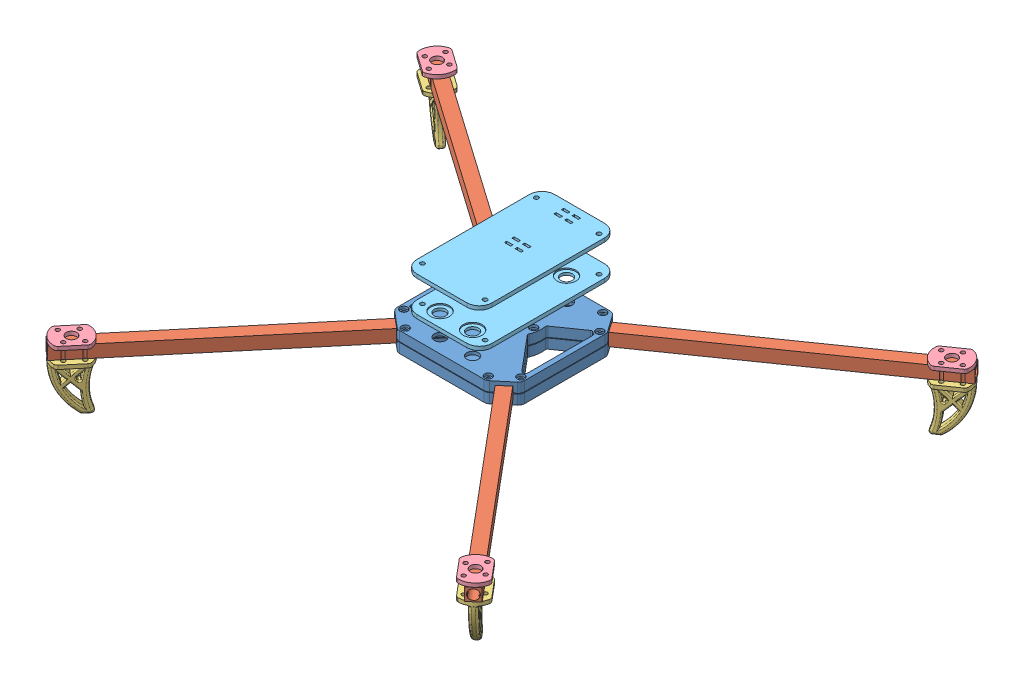
SolidWorks assembly Carbon Arm Quad, configuration Default. Lengths in mm.
Overall size (449.5 99 372.79).
16 component instances, 5 part files, 45 mates.
Components (placement in the parent):
- Center Section-1: Center Section [Bottom] at origin size (101.58 8.23 97.56)
- Center Section-2: Center Section [Top] x (-1 0 0) z (0 0 1) size (101.58 8.23 97.56)
- Carbon Arm-1: Carbon Arm [Default] at (-9.6418 0 11.4907) x (0.766044 0 0.642788) z (-0.642788 0 0.766044) size (10 10 250)
- Carbon Arm-2: Carbon Arm [Default] at (-12.2873 0 -8.6036) x (-0.573576 0 0.819152) z (-0.819152 0 -0.573576) size (10 10 250)
- Carbon Arm-5: Carbon Arm [Default] at (12.2873 0 -8.6036) x (-0.573576 0 -0.819152) z (0.819152 0 -0.573576) size (10 10 250)
- Carbon Arm-6: Carbon Arm [Default] at (9.6418 0 11.4907) x (0.766044 0 -0.642788) z (0.642788 0 0.766044) size (10 10 250)
- Bottom Motor Mount-1: Bottom Motor Mount [Default] at (-205.6072 5 -143.9677) x (-0.573576 0 0.819152) z (-0.819152 0 -0.573576) size (20 40 32.07)
- Top Motor Mount-1: Top Motor Mount [Default] at (-205.6072 5 -143.9677) x (-0.573576 0 0.819152) z (-0.819152 0 -0.573576) size (20 3 28)
- Bottom Motor Mount-3: Bottom Motor Mount [Default] at (-161.3397 5 192.2772) x (0.766044 0 0.642788) z (-0.642788 0 0.766044) size (20 40 32.07)
- Top Motor Mount-2: Top Motor Mount [Default] at (-161.3397 5 192.2772) x (0.766044 0 0.642788) z (-0.642788 0 0.766044) size (20 3 28)
- Bottom Motor Mount-5: Bottom Motor Mount [Default] at (161.3397 5 192.2772) x (0.766044 0 -0.642788) z (0.642788 0 0.766044) size (20 40 32.07)
- Top Motor Mount-4: Top Motor Mount [Default] at (161.3397 5 192.2772) x (0.766044 0 -0.642788) z (0.642788 0 0.766044) size (20 3 28)
- Bottom Motor Mount-6: Bottom Motor Mount [Default] at (205.6072 5 -143.9677) x (-0.573576 0 -0.819152) z (0.819152 0 -0.573576) size (20 40 32.07)
- Top Motor Mount-5: Top Motor Mount [Default] at (205.6072 5 -143.9677) x (-0.573576 0 -0.819152) z (0.819152 0 -0.573576) size (20 3 28)
- Clean Plate-1: Clean Plate [Bottom] at (0 23 2.8266) size (60 3 110)
- Clean Plate-2: Clean Plate [Top] at (0 51 2.8266) size (60 3 110)
Mates (geometry in assembly coordinates):
- Distance1: distance = 0.5 mm anti-aligned: plane of Center Section-2 through (0 0.25 0) normal (0 -1 0); plane of Center Section-1 through (0 -0.25 0) normal (0 1 0)
- Concentric1: concentric anti-aligned: cylinder of Center Section-1 through (0 -45.7262 0) axis (0 1 0) radius 14; cylinder of Center Section-2 through (0 45.7262 0) axis (0 -1 0) radius 14
- Coincident2: coincident aligned: plane of Center Section-1 through (35.4682 -0.25 57.8266) normal (0 0 1); plane of Center Section-2 through (-35.4682 0.25 57.8266) normal (0 0 1)
- Coincident3: coincident anti-aligned: plane of Center Section-1 through (0 -5 0) normal (0 1 0); plane of Carbon Arm-1 through (-174.1689 -5 199.7878) normal (0 -1 0)
- Coincident4: coincident anti-aligned: plane of Center Section-1 through (-5.6584 5 14.8332) normal (-0.642788 0 0.766044); plane of Carbon Arm-1 through (-9.6418 0 11.4907) normal (0.642788 0 -0.766044)
- Width1: width anti-aligned: plane of Carbon Arm-1 through (-166.5085 5 206.2157) normal (0.766044 0 0.642788); plane of Carbon Arm-1 through (-174.1689 5 199.7878) normal (-0.766044 0 -0.642788); plane of Center Section-1 through (-5.6584 5 14.8332) normal (-0.766044 0 -0.642788); plane of Center Section-1 through (-13.6252 5 8.1482) normal (0.766044 0 0.642788)
- Coincident5: coincident anti-aligned: plane of Center Section-1 through (-9.3047 5 -12.8632) normal (-0.819152 0 -0.573576); plane of Carbon Arm-2 through (-12.2873 0 -8.6036) normal (0.819152 0 0.573576)
- Coincident6: coincident anti-aligned: plane of Center Section-1 through (0 -5 0) normal (0 1 0); plane of Carbon Arm-2 through (-214.2074 -5 -156.0935) normal (0 -1 0)
- Width2: width aligned: plane of Carbon Arm-2 through (-219.9432 5 -147.902) normal (-0.573576 0 0.819152); plane of Carbon Arm-2 through (-214.2074 5 -156.0935) normal (0.573576 0 -0.819152); plane of Center Section-1 through (-42.0708 5 -35.8063) normal (-0.573576 0 0.819152); plane of Center Section-1 through (-48.036 5 -27.2871) normal (0.573576 0 -0.819152)
- Coincident7: coincident anti-aligned: plane of Center Section-2 through (9.3047 -5 -12.8632) normal (0.819152 0 -0.573576); plane of Carbon Arm-5 through (12.2873 0 -8.6036) normal (-0.819152 0 0.573576)
- Coincident8: coincident anti-aligned: plane of Center Section-1 through (0 -5 0) normal (0 1 0); plane of Carbon Arm-5 through (219.9432 -5 -147.902) normal (0 -1 0)
- Width3: width aligned: plane of Carbon Arm-5 through (219.9432 5 -147.902) normal (0.573576 0 0.819152); plane of Carbon Arm-5 through (214.2074 5 -156.0935) normal (-0.573576 0 -0.819152); plane of Center Section-1 through (42.0708 5 -35.8063) normal (0.573576 0 0.819152); plane of Center Section-1 through (48.036 5 -27.2871) normal (-0.573576 0 -0.819152)
- Coincident9: coincident anti-aligned: plane of Center Section-2 through (0 5 0) normal (0 -1 0); plane of Carbon Arm-6 through (166.5085 5 206.2157) normal (0 1 0)
- Coincident10: coincident anti-aligned: plane of Center Section-2 through (5.6584 -5 14.8332) normal (0.642788 0 0.766044); plane of Carbon Arm-6 through (9.6418 0 11.4907) normal (-0.642788 0 -0.766044)
- Width4: width anti-aligned: plane of Carbon Arm-6 through (174.1689 5 199.7878) normal (0.766044 0 -0.642788); plane of Carbon Arm-6 through (166.5085 5 206.2157) normal (-0.766044 0 0.642788); plane of Center Section-1 through (13.6252 5 8.1482) normal (-0.766044 0 0.642788); plane of Center Section-1 through (5.6584 5 14.8332) normal (0.766044 0 -0.642788)
- Concentric2: concentric aligned: cylinder of Carbon Arm-2 through (-208.0498 5 -153.1483) axis (0 -1 0) radius 1.6; cylinder of Top Motor Mount-1 through (-208.0498 8 -153.1483) axis (0 -1 0) radius 1.6
- Concentric3: concentric aligned: cylinder of Carbon Arm-2 through (-203.1645 5 -134.7871) axis (0 -1 0) radius 1.6; cylinder of Top Motor Mount-1 through (-203.1645 8 -134.7871) axis (0 -1 0) radius 1.6
- Coincident11: coincident anti-aligned: plane of Carbon Arm-2 through (-214.2074 5 -156.0935) normal (0 1 0); plane of Top Motor Mount-1 through (-205.6072 5 -143.9677) normal (0 -1 0)
- Coincident12: coincident aligned: plane of Bottom Motor Mount-1 through (-218.2937 -8 -140.6431) normal (-0.573576 0 0.819152); plane of Top Motor Mount-1 through (-203.3169 8 -130.1563) normal (-0.573576 0 0.819152)
- Coincident13: coincident anti-aligned: plane of Carbon Arm-2 through (-214.2074 -5 -156.0935) normal (0 -1 0); plane of Bottom Motor Mount-1 through (-216.5729 -5 -143.1006) normal (0 1 0)
- Coincident14: coincident aligned: cylinder of Bottom Motor Mount-1 through (-203.1645 -8 -134.7871) axis (0 1 0) radius 1.6; circle of Top Motor Mount-1
- Coincident16: coincident aligned: plane of Bottom Motor Mount-3 through (-159.1335 -8 205.2051) normal (0.766044 0 0.642788); plane of Top Motor Mount-2 through (-147.3812 8 191.1994) normal (0.766044 0 0.642788)
- Coincident17: coincident aligned: cylinder of Bottom Motor Mount-3 through (-151.9811 -8 190.644) axis (0 1 0) radius 1.6; circle of Top Motor Mount-2
- Concentric4: concentric aligned: cylinder of Carbon Arm-1 through (-170.6983 5 193.9103) axis (0 -1 0) radius 1.6; cylinder of Top Motor Mount-2 through (-170.6983 8 193.9103) axis (0 -1 0) radius 1.6
- Concentric5: concentric aligned: cylinder of Carbon Arm-1 through (-151.9811 5 190.644) axis (0 -1 0) radius 1.6; cylinder of Top Motor Mount-2 through (-151.9811 8 190.644) axis (0 -1 0) radius 1.6
- Coincident19: coincident anti-aligned: plane of Carbon Arm-2 through (-214.2074 5 -156.0935) normal (0 1 0); plane of Top Motor Mount-2 through (-161.3397 5 192.2772) normal (0 -1 0)
- Coincident20: coincident anti-aligned: plane of Carbon Arm-2 through (-214.2074 -5 -156.0935) normal (0 -1 0); plane of Bottom Motor Mount-3 through (-161.4316 -5 203.2768) normal (0 1 0)
- Coincident25: coincident aligned: plane of Bottom Motor Mount-5 through (174.4544 -8 192.3494) normal (0.766044 0 -0.642788); plane of Top Motor Mount-4 through (162.7021 8 178.3436) normal (0.766044 0 -0.642788)
- Coincident26: coincident aligned: cylinder of Bottom Motor Mount-5 through (161.3564 -8 182.7772) axis (0 1 0) radius 1.6; circle of Top Motor Mount-4
- Concentric7: concentric aligned: cylinder of Carbon Arm-6 through (161.323 5 201.7771) axis (0 -1 0) radius 1.6; cylinder of Top Motor Mount-4 through (161.323 8 201.7771) axis (0 -1 0) radius 1.6
- Coincident27: coincident anti-aligned: plane of Carbon Arm-2 through (-214.2074 5 -156.0935) normal (0 1 0); plane of Top Motor Mount-4 through (161.3397 5 192.2772) normal (0 -1 0)
- Coincident28: coincident anti-aligned: plane of Carbon Arm-2 through (-214.2074 -5 -156.0935) normal (0 -1 0); plane of Bottom Motor Mount-5 through (172.1562 -5 194.2777) normal (0 1 0)
- Concentric8: concentric aligned: cylinder of Carbon Arm-6 through (161.3564 5 182.7772) axis (0 -1 0) radius 1.6; cylinder of Top Motor Mount-4 through (161.3564 8 182.7772) axis (0 -1 0) radius 1.6
- Coincident29: coincident aligned: plane of Bottom Motor Mount-6 through (206.8221 -8 -157.0262) normal (-0.573576 0 -0.819152); plane of Top Motor Mount-5 through (191.8454 8 -146.5393) normal (-0.573576 0 -0.819152)
- Coincident30: coincident aligned: cylinder of Bottom Motor Mount-6 through (196.1448 -8 -144.8123) axis (0 1 0) radius 1.6; circle of Top Motor Mount-5
- Concentric9: concentric aligned: cylinder of Carbon Arm-5 through (215.0695 5 -143.123) axis (0 -1 0) radius 1.6; cylinder of Top Motor Mount-5 through (215.0695 8 -143.123) axis (0 -1 0) radius 1.6
- Coincident31: coincident anti-aligned: plane of Carbon Arm-2 through (-214.2074 5 -156.0935) normal (0 1 0); plane of Top Motor Mount-5 through (205.6072 5 -143.9677) normal (0 -1 0)
- Coincident32: coincident anti-aligned: plane of Carbon Arm-2 through (-214.2074 -5 -156.0935) normal (0 -1 0); plane of Bottom Motor Mount-6 through (208.5429 -5 -154.5687) normal (0 1 0)
- Concentric10: concentric aligned: cylinder of Carbon Arm-5 through (196.1448 5 -144.8123) axis (0 -1 0) radius 1.6; cylinder of Top Motor Mount-5 through (196.1448 8 -144.8123) axis (0 -1 0) radius 1.6
- Distance2: distance = 15 mm anti-aligned: plane of Clean Plate-1 through (0 23 2.8266) normal (0 -1 0); plane of Center Section-2 through (0 8 0) normal (0 1 0)
- Coincident34: coincident aligned: plane of Clean Plate-1 through (0 23 2.8266) normal (1 0 0); plane of assembly through (0 0 0) normal (1 0 0)
- Coincident35: coincident aligned: plane of Center Section-2 through (-35.4682 0.25 57.8266) normal (0 0 1); plane of Clean Plate-1 through (-30 26 57.8266) normal (0 0 1)
- Distance3: distance = 25 mm anti-aligned: plane of Clean Plate-1 through (0 26 2.8266) normal (0 1 0); plane of Clean Plate-2 through (0 51 2.8266) normal (0 -1 0)
- Concentric11: concentric aligned: cylinder of Clean Plate-1 through (25 26 -42.6734) axis (0 1 0) radius 1.7; cylinder of Clean Plate-2 through (25 54 -42.6734) axis (0 1 0) radius 1.7
- Concentric12: concentric aligned: cylinder of Clean Plate-1 through (-25 26 48.3266) axis (0 1 0) radius 1.7; cylinder of Clean Plate-2 through (-25 54 48.3266) axis (0 1 0) radius 1.7
